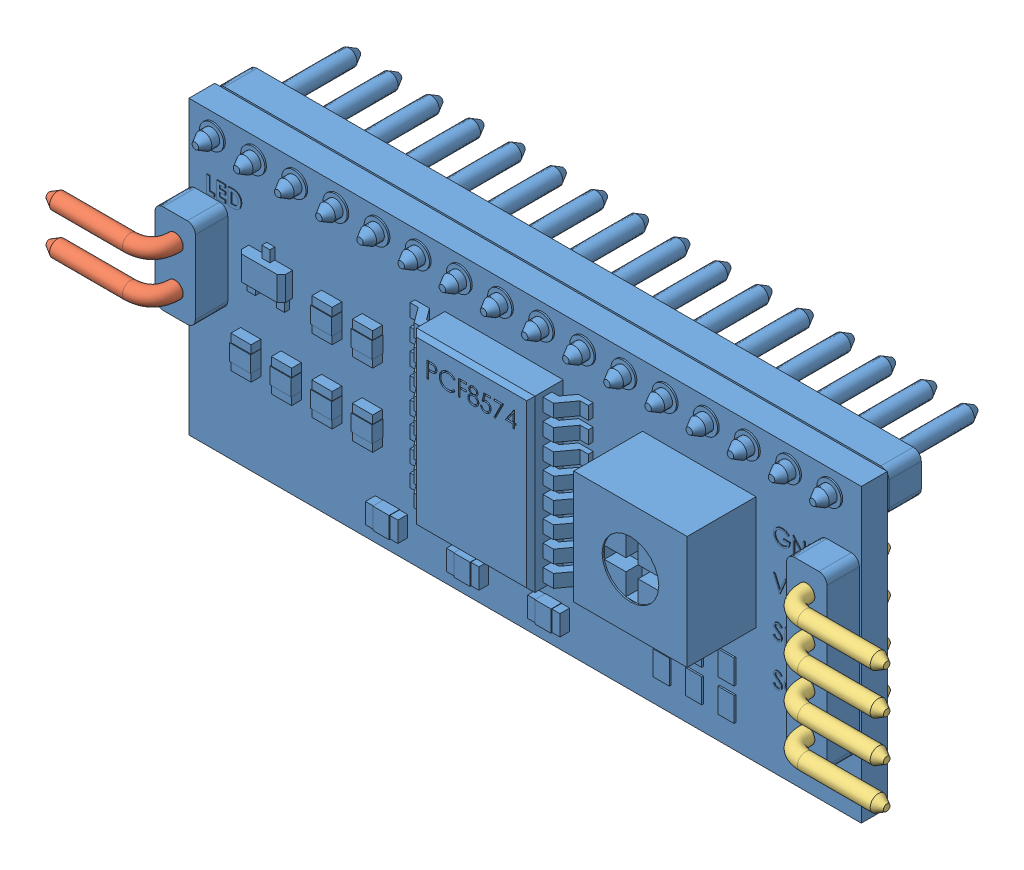
SolidWorks assembly Assem1, configuration Default. Lengths in mm.
Overall size (51.69 18 13.15).
3 component instances, 3 part files, 4 mates.
Components (placement in the parent):
- I2C LCD Adapter PCF8574-1: I2C LCD Adapter PCF8574 [Default] at (17.1002 19.9725 32.15) size (41.5 18 13.15)
- 2 way header curved-1: 2 way header curved [Default] at (-2.3998 20.4325 35.1805) x (-1 0 0) z (0 1 0) size (6.86 6.88 3.54)
- 4 way header curved-1: 4 way header curved [Default] at (36.5802 23.7225 35.1852) x (1 0 0) z (0 -1 0) size (6.86 6.88 8.62)
Mates (geometry in assembly coordinates):
- Concentric6: concentric: cylinder of I2C LCD Adapter PCF8574-1 through (-2.3998 22.9725 32.05) axis (0 0 1) radius 0.5; cylinder of 2 way header curved-1 through (-2.3998 22.9725 37.2939) axis (0 0 -1) radius 0.5
- Concentric7: concentric anti-aligned: cylinder of I2C LCD Adapter PCF8574-1 through (-2.3998 20.4325 32.05) axis (0 0 1) radius 0.5; cylinder of 2 way header curved-1 through (-2.3998 20.4325 37.2939) axis (0 0 -1) radius 0.5
- Concentric8: concentric anti-aligned: cylinder of I2C LCD Adapter PCF8574-1 through (36.5802 23.7225 32.05) axis (0 0 1) radius 0.5; cylinder of 4 way header curved-1 through (36.5802 23.7225 37.2986) axis (0 0 -1) radius 0.5
- Concentric9: concentric anti-aligned: cylinder of I2C LCD Adapter PCF8574-1 through (36.5802 16.1025 32.05) axis (0 0 1) radius 0.5; cylinder of 4 way header curved-1 through (36.5802 16.1025 37.2986) axis (0 0 -1) radius 0.5
